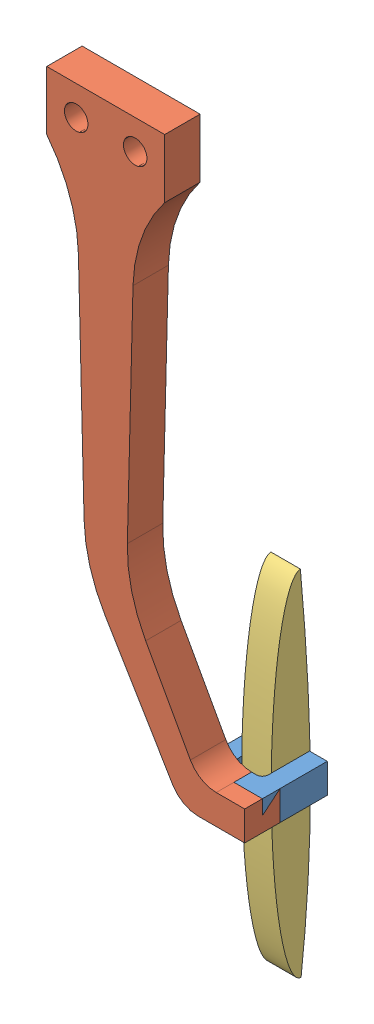
SolidWorks assembly Left Wiper, configuration Default. Lengths in mm.
Overall size (33.56 124.74 14.18).
3 component instances, 3 part files, 4 mates.
Components (placement in the parent):
- Hinge-1: Hinge [Default] at (-6.8541 -36.9888 25.6192) size (11 5 11)
- WiperArm-1: WiperArm [Default] at (-24.9155 55.242 28.1192) size (33.56 97.23 6)
- Wiper Blade-1: Wiper Blade [Default] at (-9.3541 -4.4839 21.6786) x (1 0 0) z (0 -0.001982 0.999998) size (5 60 6.62)
Mates (geometry in assembly coordinates):
- Coincident2: coincident: plane of Hinge-1 through (-6.8541 -36.9888 25.6192) normal (0 -1 0); plane of WiperArm-1 through (-24.9155 -36.9888 34.1192) normal (0 -1 0)
- Coincident4: coincident: circle of Hinge-1; circle of Wiper Blade-1
- Coincident5: coincident: plane of Hinge-1 through (-1.3541 -31.9888 25.6192) normal (1 0 0); plane of WiperArm-1 through (-1.3541 55.242 34.1192) normal (1 0 0)
- Coincident6: coincident: plane of Hinge-1 through (-6.8541 -31.9888 28.1192) normal (0 0 -1); plane of WiperArm-1 through (-24.9155 55.242 28.1192) normal (0 0 -1)
